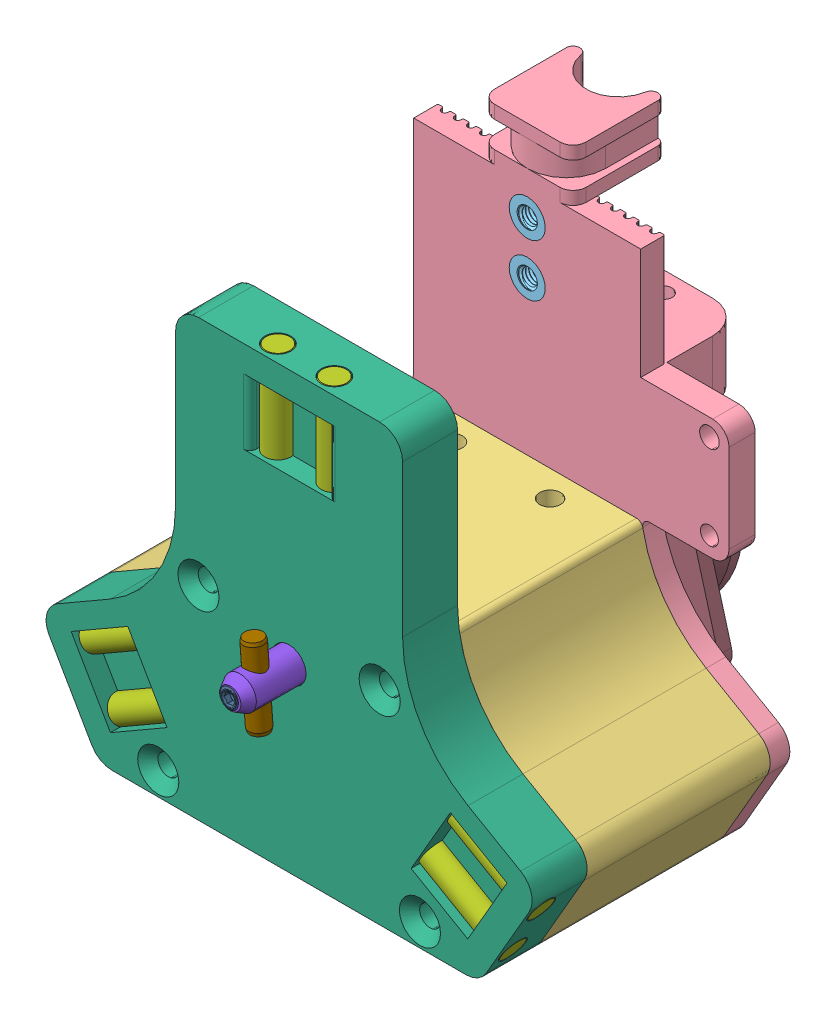
SolidWorks assembly Assem1, configuration Default. Lengths in mm.
Overall size (74.69 85.22 62.67).
25 component instances, 14 part files, 19 mates.
Components (placement in the parent):
- center_carriage_assembly-1: center_carriage_assembly [Default] at origin size (74.3 41.27 29.98)
  - D2HW_C201H-1: D2HW_C201H [Default] at (97.5575 350.9116 64.7434) x (1 0 0) z (0 0 -1) size (18.5 14.2 8.3)
  - m3_8mm_buttonhead_screw_92095A181_92095A181-1: m3_8mm_buttonhead_screw_92095A181_92095A181 [Default] at (110.5575 350.9116 71.6934) x (0.795507 0.605945 0) z (0 0 1) size (5.74 5.77 10.05)
  - coupling_plate_Carriage Center Plate-1: coupling_plate_Carriage Center Plate [Default] at (97.5575 375.4795 75.9434) size (74.3 37.07 28.05)
- carriage_back_plate_with_inserts-1: carriage_back_plate_with_inserts [Default] at origin size (74.3 81.02 16.04)
  - coupling_plate_Carriage Back Plate-1: coupling_plate_Carriage Back Plate [Default] at (97.5575 375.4795 75.9434) size (74.3 81.02 16)
  - m3_heat_set_insert_94180A331_94180A331-1: m3_heat_set_insert_94180A331_94180A331 [Default] at (97.5575 416.4295 42.1434) x (0.303083 -0.952964 0) z (-0.952964 -0.303083 0) size (5.56 3.88 5.56)
  - m3_heat_set_insert_94180A331_94180A331-2: m3_heat_set_insert_94180A331_94180A331 [Default] at (97.5575 408.4295 42.1434) x (0.303083 -0.952964 0) z (-0.952964 -0.303083 0) size (5.56 3.88 5.56)
- coupling_plate_assembly-1: coupling_plate_assembly [Default] at origin size (74.69 66.57 8.62)
  - coupling_plate_Carriage Coupler Plate-1: coupling_plate_Carriage Coupler Plate [Default] at (97.5575 375.4795 75.9434) size (74.3 66.57 8.4)
  - dowel_pin_4mm_d_20mm_l_91585A457_91585A457-1: dowel_pin_4mm_d_20mm_l_91585A457_91585A457 [Default] at (93.2415 404.4795 75.9434) x (0 1 0) z (0.777637 0 0.628713) size (20 4 4)
  - dowel_pin_4mm_d_20mm_l_91585A457_91585A457-2: dowel_pin_4mm_d_20mm_l_91585A457_91585A457 [Default] at (101.8736 404.4795 75.9434) x (0 1 0) z (0.784909 0 0.619611) size (20 4 4)
  - dowel_pin_4mm_d_20mm_l_91585A457_91585A457-3: dowel_pin_4mm_d_20mm_l_91585A457_91585A457 [Default] at (70.2848 364.7173 75.9434) x (-0.866025 -0.5 0) z (-0.329564 0.570821 0.752031) size (20 4 4)
  - dowel_pin_4mm_d_20mm_l_91585A457_91585A457-4: dowel_pin_4mm_d_20mm_l_91585A457_91585A457 [Default] at (74.6008 357.2417 75.9434) x (-0.866025 -0.5 0) z (-0.329564 0.570821 0.752031) size (20 4 4)
  - dowel_pin_4mm_d_20mm_l_91585A457_91585A457-5: dowel_pin_4mm_d_20mm_l_91585A457_91585A457 [Default] at (120.5142 357.2417 75.9434) x (-0.866025 0.5 0) z (0.329564 0.570821 0.752031) size (20 4 4)
  - dowel_pin_4mm_d_20mm_l_91585A457_91585A457-6: dowel_pin_4mm_d_20mm_l_91585A457_91585A457 [Default] at (124.8303 364.7173 75.9434) x (-0.866025 0.5 0) z (0.329564 0.570821 0.752031) size (20 4 4)
- twist_lock_assembly-1: twist_lock_assembly [Default] at (-284.2866 444.0171 0.2) x (0.076526 -0.997068 0) z (0 0 1) size (14.14 14.14 62.67)
  - tool_lock-1: tool_lock [Default] at (97.5575 375.4795 24.9934) x (0 -1 0) z (-1 0 0) size (5 62.34 5)
  - dowel_pin_3mm_d_12mm_l_91585A371-1: dowel_pin_3mm_d_12mm_l_91585A371 [Default] at (97.5575 375.4795 83.3361) x (-1 0 0) z (0 0.411258 0.911519) size (12 3 3)
  - m3_set_screw_3mm_92015A101_92015A101-1: m3_set_screw_3mm_92015A101_92015A101 [Default] at (97.5575 375.4795 86.3378) x (0.998583 0.053214 0) z (0 0 1) size (3.09 3.01 3.07)
  - e_clip_98543A103_98543A103-1: e_clip_98543A103_98543A103 [Default] at (97.5575 375.4795 42.4434) x (0 0 -1) z (0.999491 -0.031891 0) size (0.6 6.9 6.33)
  - m5_shim_0.2mm_thick_98089A246_98089A246-1: m5_shim_0.2mm_thick_98089A246_98089A246 [Default] at (97.5575 375.4795 42.1434) x (0.716209 -0.697886 0) z (0.697886 0.716209 0) size (10 0.2 10)
- carriage_pulley-1: carriage_pulley [Default] at (97.5575 375.4795 33.1934) x (-0.997068 -0.076526 0) z (0.076526 -0.997068 0) size (38.8 8 35.9)
- m5_belleville_disc_spring_96475K215_96475K215-1: m5_belleville_disc_spring_96475K215_96475K215 [Default] at (97.5575 375.4795 34.1434) x (-0.423312 -0.905984 0) z (0.905984 -0.423312 0) size (10 0.75 10)
- m5_shim_0.2mm_thick_98089A246_98089A246-1: m5_shim_0.2mm_thick_98089A246_98089A246 [Default] at (97.5575 375.4795 33.3934) x (1 0 0) z (0 1 0) size (10 0.2 10)
Mates (geometry in assembly coordinates):
- Concentric1: concentric aligned: cylinder of center_carriage_assembly-1/coupling_plate_Carriage Center Plate-1 through (83.7075 378.9795 60.1434) axis (0 0 1) radius 1.35; cylinder of coupling_plate_assembly-1/coupling_plate_Carriage Coupler Plate-1 through (83.7075 378.9795 78.5434) axis (0 0 1) radius 1.6
- Concentric2: concentric aligned: cylinder of center_carriage_assembly-1/coupling_plate_Carriage Center Plate-1 through (111.4075 378.9795 60.1434) axis (0 0 1) radius 1.35; cylinder of coupling_plate_assembly-1/coupling_plate_Carriage Coupler Plate-1 through (111.4075 378.9795 78.5434) axis (0 0 1) radius 1.6
- Concentric3: concentric aligned: cylinder of center_carriage_assembly-1/coupling_plate_Carriage Center Plate-1 through (77.5575 351.4116 60.1434) axis (0 0 1) radius 1.35; cylinder of coupling_plate_assembly-1/coupling_plate_Carriage Coupler Plate-1 through (77.5575 351.4116 78.5434) axis (0 0 1) radius 1.6
- Concentric4: concentric aligned: cylinder of center_carriage_assembly-1/coupling_plate_Carriage Center Plate-1 through (117.5575 351.4116 60.1434) axis (0 0 1) radius 1.35; cylinder of coupling_plate_assembly-1/coupling_plate_Carriage Coupler Plate-1 through (117.5575 351.4116 78.5434) axis (0 0 1) radius 1.6
- Coincident1: coincident anti-aligned: plane of center_carriage_assembly-1/coupling_plate_Carriage Center Plate-1 through (134.9075 387.7667 70.1434) normal (0 0 1); plane of coupling_plate_assembly-1/coupling_plate_Carriage Coupler Plate-1 through (97.5575 375.4795 70.1434) normal (0 0 -1)
- Concentric5: concentric aligned: cylinder of center_carriage_assembly-1/coupling_plate_Carriage Center Plate-1 through (77.5575 351.4116 52.1434) axis (0 0 -1) radius 1.35; cylinder of carriage_back_plate_with_inserts-1/coupling_plate_Carriage Back Plate-1 through (77.5575 351.4116 39.1434) axis (0 0 -1) radius 1.6
- Concentric6: concentric aligned: cylinder of center_carriage_assembly-1/coupling_plate_Carriage Center Plate-1 through (117.5575 351.4116 52.1434) axis (0 0 -1) radius 1.35; cylinder of carriage_back_plate_with_inserts-1/coupling_plate_Carriage Back Plate-1 through (117.5575 351.4116 39.1434) axis (0 0 -1) radius 1.6
- Concentric7: concentric aligned: cylinder of center_carriage_assembly-1/coupling_plate_Carriage Center Plate-1 through (111.4075 378.9795 52.1434) axis (0 0 -1) radius 1.35; cylinder of carriage_back_plate_with_inserts-1/coupling_plate_Carriage Back Plate-1 through (111.4075 378.9795 39.1434) axis (0 0 -1) radius 1.6
- Concentric8: concentric aligned: cylinder of center_carriage_assembly-1/coupling_plate_Carriage Center Plate-1 through (83.7075 378.9795 52.1434) axis (0 0 -1) radius 1.35; cylinder of carriage_back_plate_with_inserts-1/coupling_plate_Carriage Back Plate-1 through (83.7075 378.9795 39.1434) axis (0 0 -1) radius 1.6
- Coincident2: coincident anti-aligned: plane of center_carriage_assembly-1/coupling_plate_Carriage Center Plate-1 through (134.9075 387.7667 42.1434) normal (0 0 -1); plane of carriage_back_plate_with_inserts-1/coupling_plate_Carriage Back Plate-1 through (134.9075 387.7667 42.1434) normal (0 0 1)
- Concentric9: concentric anti-aligned: cone of coupling_plate_assembly-1/coupling_plate_Carriage Coupler Plate-1 through (97.5575 375.4795 70.1434) axis (0 0 1); cylinder of twist_lock_assembly-1/tool_lock-1 through (97.5575 375.4795 87.5361) axis (0 0 -1) radius 2.5
- Concentric10: concentric anti-aligned: cylinder of twist_lock_assembly-1/tool_lock-1 through (97.5575 375.4795 87.5361) axis (0 0 -1) radius 2.5; cylinder of carriage_pulley-1 through (97.5575 375.4795 25.1924) axis (0 0 1) radius 2.575
- Parallel1: parallel aligned: plane of twist_lock_assembly-1/tool_lock-1 through (99.2444 373.1017 25.1934) normal (0.997068 0.076526 0); plane of carriage_pulley-1 through (101.3392 378.4777 30.5934) normal (0.997068 0.076526 0)
- Coincident6: coincident anti-aligned: plane of carriage_back_plate_with_inserts-1/coupling_plate_Carriage Back Plate-1 through (134.9075 387.7667 42.1434) normal (0 0 1); plane of twist_lock_assembly-1/m5_shim_0.2mm_thick_98089A246_98089A246-1 through (97.5575 375.4795 42.1434) normal (0 0 -1)
- Concentric11: concentric anti-aligned: cylinder of twist_lock_assembly-1/tool_lock-1 through (97.5575 375.4795 87.5361) axis (0 0 -1) radius 2.5; cone of m5_belleville_disc_spring_96475K215_96475K215-1 through (97.5575 375.4795 33.3934) axis (0 0 1)
- Coincident10: coincident aligned: plane of carriage_back_plate_with_inserts-1/coupling_plate_Carriage Back Plate-1 through (97.5575 375.4795 34.1434) normal (0 0 -1); circle of m5_belleville_disc_spring_96475K215_96475K215-1
- Concentric12: concentric aligned: cylinder of twist_lock_assembly-1/tool_lock-1 through (97.5575 375.4795 87.5361) axis (0 0 -1) radius 2.5; cylinder of m5_shim_0.2mm_thick_98089A246_98089A246-1 through (97.5575 375.4795 33.3934) axis (0 0 -1) radius 2.5
- Coincident11: coincident anti-aligned: plane of carriage_pulley-1 through (97.5575 375.4795 33.1934) normal (0 0 1); plane of m5_shim_0.2mm_thick_98089A246_98089A246-1 through (97.5575 375.4795 33.1934) normal (0 0 -1)
- Coincident12: coincident aligned: plane of twist_lock_assembly-1/tool_lock-1 through (97.5575 375.4795 25.1934) normal (0 0 -1); plane of carriage_pulley-1 through (81.1059 374.2169 25.1934) normal (0 0 -1)
